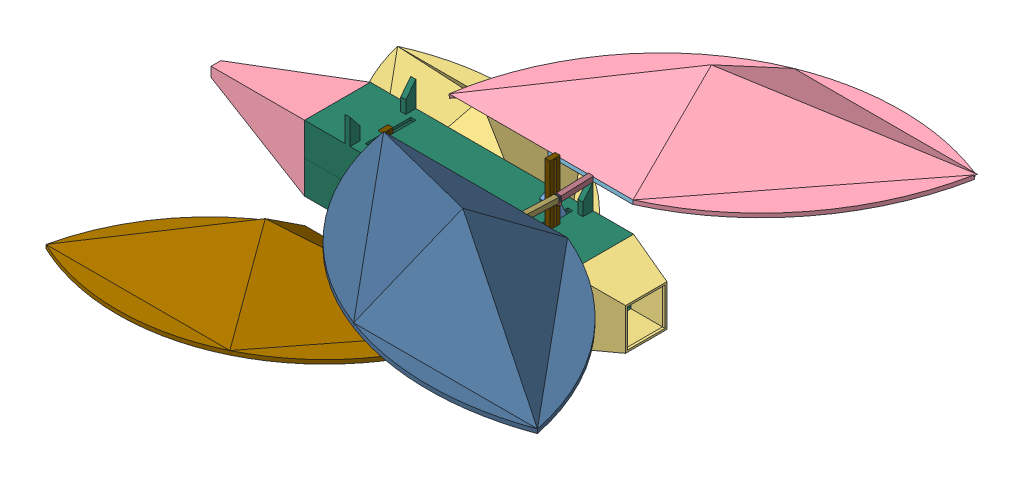
SolidWorks assembly butterfly_CAD_assembly_revised, configuration Default. Lengths in mm.
Overall size (339.79 140.22 297.7).
26 component instances, 22 part files, 59 mates.
Components (placement in the parent):
- part_MECHANICALlargegear_revised-1: part_MECHANICALlargegear_revised [Default] at (-285.4222 85.9127 91.299) x (1 0 0) z (0 -0.999999 0.001095) size (101.6 25.4 6.35)
- part_MECHANICALmotor_revised-1: part_MECHANICALmotor_revised [Default] at (-320.7441 85.9197 97.649) size (24.61 15.88 19.05)
- part_WINGleft-back-1: part_WINGleft-back [Default] at (-467.9022 47.8673 32.872) x (1 0 0) z (0 0.034865 0.999392) size (189.43 39.71 101.22)
- part_WINGleft-front-1: part_WINGleft-front [Default] at (-259.0359 127.2619 18.3121) x (1 0 0) z (0 -0.036788 0.999323) size (214.05 40.94 128.15)
- part_WINGpylon1-1: part_WINGpylon1 [Default] at (-278.8182 118.2238 89.6169) x (1 0 0) z (0 -0.786398 0.61772) size (53.47 17.42 15.33)
- part_WINGpylon2-1: part_WINGpylon2 [Default] at (-389.9432 43.4468 89.9789) x (1 0 0) z (0 -0.740147 0.672445) size (53.47 17.42 15.33)
- part_WINGpylon3-1: part_WINGpylon3 [Default] at (-389.9432 40.9247 125.4869) x (1 0 0) z (0 0.647143 0.762368) size (53.47 15.82 17.01)
- part_WINGpylon4-1: part_WINGpylon4 [Default] at (-278.8182 117.1522 125.9777) x (1 0 0) z (0 0.700073 0.714072) size (53.47 15.82 17.01)
- part_WINGright-back-1: part_WINGright-back [Default] at (-394.7481 47.8673 162.426) x (1 0 0) z (0 -0.034865 0.999392) size (189.43 40.98 101.11)
- part_WINGright-front-1: part_WINGright-front [Default] at (-259.0359 127.2619 176.9858) x (1 0 0) z (0 0.036788 0.999323) size (214.05 40.94 128.46)
- part_WINGsleeve1-1: part_WINGsleeve1 [Default] at (-388.6097 48.0586 76.6029) x (1 0 0) z (0 0.034865 0.999392) size (3.17 3.17 20.32)
- part_WINGsleeve2-1: part_WINGsleeve2 [Default] at (-277.4847 123.0339 98.3843) x (1 0 0) z (0 0.036788 0.999323) size (3.17 3.17 20.32)
- part_WINGsleeve3-1: part_WINGsleeve3 [Default] at (-277.4847 123.7815 76.6074) x (1 0 0) z (0 -0.036788 0.999323) size (3.17 3.17 20.32)
- part_WINGsleeve4-1: part_WINGsleeve4 [Default] at (-388.6097 48.7671 98.3874) x (1 0 0) z (0 -0.034865 0.999392) size (3.17 3.17 20.32)
- part_BODYshell_revised-2: part_BODYshell_revised [Default] at (-250.4972 76.3947 97.649) size (165.1 36.51 41.28)
- part_BODYmotorsupport-1: part_BODYmotorsupport [Default] at (-342.1753 72.4259 97.649) size (3.17 11.11 12.7)
- part_BODYmotorsupport1-1: part_BODYmotorsupport1 [Default] at (-320.7441 72.4259 97.649) size (3.17 11.11 12.7)
- part_MECHANICALrail_revised1-1: part_MECHANICALrail_revised1 [Default] at (-383.8472 67.2666 97.649) size (3.17 78.58 6.35)
- part_MECHANICALrail_revised1-2: part_MECHANICALrail_revised1 [Default] at (-279.0722 104.5728 97.649) size (3.17 78.58 6.35)
- part_MECHANICALpiston_revised-3: part_MECHANICALpiston_revised [Default] at (-282.2472 103.2772 88.9177) x (1 0 0) z (0 0.448979 -0.893542) size (3.17 42.07 6.35)
- part_BODYshell_revised-3: part_BODYshell_revised [Default] at (-250.4972 95.4447 97.649) x (1 0 0) z (0 0 -1) size (165.1 36.51 41.28)
- part_MECHANICALpin_revised-1: part_MECHANICALpin_revised [Default] at (-282.2472 120.6538 97.649) size (9.52 1.59 1.59)
- part_MECHANICALpin_revised-2: part_MECHANICALpin_revised [Default] at (-383.8472 51.1474 97.649) x (-1 0 0) z (0 0 -1) size (9.52 1.59 1.59)
- part_MECHANICALpiston_revised-4: part_MECHANICALpiston_revised [Default] at (-380.6722 68.524 88.9177) x (1 0 0) z (0 0.448979 0.893542) size (3.17 42.07 6.35)
- part_BODYnosecone_revised-1: part_BODYnosecone_revised [Default] at (-250.4972 87.5072 96.0615) size (28.57 41.28 41.28)
- part_BODYabdomencone_revised-1: part_BODYabdomencone_revised [Default] at (-415.5972 85.9197 97.649) size (76.2 41.27 41.27)
Mates (geometry in assembly coordinates):
- Concentric1: concentric aligned: cylinder of part_MECHANICALlargegear_revised-1 through (-377.4972 85.9197 97.649) axis (1 0 0) radius 0.7937; cylinder of part_MECHANICALmotor_revised-1 through (-345.3503 85.9197 97.649) axis (1 0 0) radius 0.7937
- Coincident1: coincident aligned: line of part_MECHANICALmotor_revised-1 through (-345.3503 77.9822 103.999) axis (1 0 0); line of part_BODYmotorsupport-1 through (-345.3503 77.9822 103.999) axis (1 0 0)
- Coincident2: coincident anti-aligned: line of part_MECHANICALmotor_revised-1 through (-345.3503 77.9822 103.999) axis (0 0 -1); line of part_BODYmotorsupport-1 through (-345.3503 77.9822 91.299) axis (0 0 1)
- Coincident4: coincident aligned: line of part_MECHANICALmotor_revised-1 through (-345.3503 77.9822 103.999) axis (1 0 0); line of part_BODYmotorsupport1-1 through (-323.9191 77.9822 103.999) axis (1 0 0)
- Coincident5: coincident anti-aligned: line of part_MECHANICALmotor_revised-1 through (-320.7441 77.9822 103.999) axis (0 0 -1); line of part_BODYmotorsupport1-1 through (-320.7441 77.9822 91.299) axis (0 0 1)
- Coincident6: coincident aligned: line of part_BODYshell_revised-2 through (-320.7441 66.8697 103.999) axis (0 0 -1); line of part_BODYmotorsupport1-1 through (-320.7441 66.8697 103.999) axis (0 0 -1)
- Coincident8: coincident aligned: line of part_BODYshell_revised-2 through (-345.3503 66.8697 103.999) axis (1 0 0); line of part_BODYmotorsupport-1 through (-345.3503 66.8697 103.999) axis (1 0 0)
- Symmetric1: symmetric anti-aligned: line of part_MECHANICALlargegear_revised-1 through (-288.5972 89.1016 103.9955) axis (0 -0.999999 0.001095); line of part_MECHANICALlargegear_revised-1 through (-377.4972 82.7516 104.0024) axis (0 0.999999 -0.001095); plane of assembly
- Coincident11: coincident anti-aligned: line of part_BODYshell_revised-2 through (-279.0722 65.2822 94.474) axis (0 0 1); line of part_MECHANICALrail_revised1-2 through (-279.0722 65.2822 100.824) axis (0 0 -1)
- Coincident12: coincident anti-aligned: line of part_BODYshell_revised-2 through (-279.0722 65.2822 100.824) axis (-1 0 0); line of part_MECHANICALrail_revised1-2 through (-282.2472 65.2822 100.824) axis (1 0 0)
- Coincident16: coincident aligned: circle of part_MECHANICALlargegear_revised-1; circle of part_MECHANICALpiston_revised-3
- Coincident17: coincident aligned: line of part_BODYshell_revised-2 through (-415.5972 85.9197 118.2865) axis (1 0 0); line of part_BODYshell_revised-3 through (-415.5972 85.9197 118.2865) axis (1 0 0)
- Coincident18: coincident anti-aligned: line of part_BODYshell_revised-2 through (-250.4972 85.9197 116.699) axis (0 0 1); line of part_BODYshell_revised-3 through (-250.4972 85.9197 118.2865) axis (0 0 -1)
- Coincident19: coincident aligned: circle of part_MECHANICALpiston_revised-3; circle of part_MECHANICALpin_revised-1
- Coincident20: coincident aligned: line of part_MECHANICALrail_revised1-2 through (-282.2472 66.0759 96.8552) axis (0 1 0); line of part_MECHANICALpin_revised-1 through (-282.2472 120.6538 96.8552) axis (0 1 0)
- Coincident21: coincident anti-aligned: circle of part_MECHANICALpin_revised-2; circle of part_MECHANICALpiston_revised-4
- Coincident22: coincident anti-aligned: circle of part_MECHANICALlargegear_revised-1; circle of part_MECHANICALpiston_revised-4
- Coincident25: coincident anti-aligned: line of part_MECHANICALrail_revised1-1 through (-383.8472 105.7634 98.4427) axis (0 -1 0); line of part_MECHANICALpin_revised-2 through (-383.8472 50.3536 98.4427) axis (0 1 0)
- Coincident26: coincident anti-aligned: line of part_WINGsleeve2-1 through (-279.0722 121.4475 98.4427) axis (1 0 0); line of part_MECHANICALpin_revised-1 through (-275.8972 121.4475 98.4427) axis (-1 0 0)
- Coincident27: coincident: point of part_WINGsleeve2-1; point of part_MECHANICALpin_revised-1
- Coincident28: coincident anti-aligned: line of part_WINGsleeve3-1 through (-279.0722 121.4475 96.8552) axis (1 0 0); line of part_MECHANICALpin_revised-1 through (-275.8972 121.4475 96.8552) axis (-1 0 0)
- Coincident29: coincident: point of part_WINGsleeve3-1; point of part_MECHANICALpin_revised-1
- Coincident30: coincident anti-aligned: line of part_WINGsleeve1-1 through (-387.0222 50.3536 96.8552) axis (-1 0 0); line of part_MECHANICALpin_revised-2 through (-390.1972 50.3536 96.8552) axis (1 0 0)
- Coincident34: coincident: point of part_WINGsleeve1-1; point of part_MECHANICALpin_revised-2
- Coincident35: coincident anti-aligned: line of part_WINGsleeve4-1 through (-387.0222 50.3536 98.4427) axis (-1 0 0); line of part_MECHANICALpin_revised-2 through (-390.1972 50.3536 98.4427) axis (1 0 0)
- Coincident36: coincident: point of part_WINGsleeve4-1; point of part_MECHANICALpin_revised-2
- Coincident37: coincident aligned: line of part_WINGpylon4-1 through (-278.8182 122.4322 118.2865) axis (0 -0.036788 -0.999323); line of part_WINGsleeve2-1 through (-278.8182 122.4489 118.7396) axis (0 -0.036788 -0.999323)
- Coincident38: coincident aligned: line of part_WINGpylon4-1 through (-276.1512 122.4322 118.2865) axis (0 -0.036788 -0.999323); line of part_WINGsleeve2-1 through (-276.1512 122.4489 118.7396) axis (0 -0.036788 -0.999323)
- Coincident40: coincident anti-aligned: line of part_WINGpylon1-1 through (-276.1512 122.4322 77.0115) axis (0 -0.036788 0.999323); line of part_WINGsleeve3-1 through (-276.1512 121.7013 96.8646) axis (0 0.036788 -0.999323)
- Coincident41: coincident aligned: line of part_WINGpylon1-1 through (-278.8182 124.3499 97.4158) axis (0 0.036788 -0.999323); line of part_WINGsleeve3-1 through (-278.8182 124.3665 96.9627) axis (0 0.036788 -0.999323)
- Coincident42: coincident aligned: line of part_WINGpylon3-1 through (-389.9432 46.7418 118.1935) axis (0 0.034865 -0.999392); line of part_WINGsleeve4-1 through (-389.9432 46.7259 118.6485) axis (0 0.034865 -0.999392)
- Coincident43: coincident anti-aligned: line of part_WINGpylon3-1 through (-387.2762 50.1156 97.9788) axis (0 -0.034865 0.999392); line of part_WINGsleeve4-1 through (-387.2762 49.3913 118.7415) axis (0 0.034865 -0.999392)
- Coincident47: coincident aligned: line of part_WINGpylon4-1 through (-276.1512 122.4322 118.2865) axis (-1 0 0); line of part_BODYshell_revised-3 through (-275.8972 122.4322 118.2865) axis (-1 0 0)
- Coincident48: coincident anti-aligned: line of part_WINGpylon1-1 through (-278.8182 122.4322 77.0115) axis (1 0 0); line of part_BODYshell_revised-3 through (-275.8972 122.4322 77.0115) axis (-1 0 0)
- Coincident49: coincident anti-aligned: line of part_WINGpylon3-1 through (-389.9432 49.4072 118.2865) axis (1 0 0); line of part_BODYshell_revised-2 through (-387.0222 49.4072 118.2865) axis (-1 0 0)
- Coincident52: coincident anti-aligned: line of part_WINGpylon2-1 through (-389.9432 46.7418 77.1044) axis (0 0.034865 0.999392); line of part_WINGsleeve1-1 through (-389.9432 47.4344 96.9571) axis (0 -0.034865 -0.999392)
- Coincident53: coincident aligned: line of part_WINGpylon2-1 through (-387.2762 50.1156 97.3191) axis (0 -0.034865 -0.999392); line of part_WINGsleeve1-1 through (-387.2762 50.0998 96.8641) axis (0 -0.034865 -0.999392)
- Coincident54: coincident anti-aligned: line of part_WINGpylon2-1 through (-389.9432 49.4072 77.0115) axis (1 0 0); line of part_BODYshell_revised-2 through (-387.0222 49.4072 77.0115) axis (-1 0 0)
- Coincident63: coincident anti-aligned: line of part_WINGpylon4-1 through (-276.1512 125.0974 118.1884) axis (1 0 0); line of part_WINGright-front-1 through (-250.7512 125.0974 118.1884) axis (-1 0 0)
- Coincident64: coincident: point of part_WINGpylon4-1; point of part_WINGright-front-1
- Coincident65: coincident: line of part_WINGpylon4-1 through (-304.2182 125.1067 118.4422) axis (1 0 0); plane of part_WINGright-front-1 through (-259.0359 127.2619 176.9858) normal (0 -0.999323 0.036788)
- Coincident66: coincident anti-aligned: line of part_WINGleft-front-1 through (-250.7512 125.0974 77.1096) axis (-1 0 0); line of part_WINGpylon1-1 through (-276.1512 125.0974 77.1096) axis (1 0 0)
- Coincident67: coincident: point of part_WINGleft-front-1; point of part_WINGpylon1-1
- Coincident68: coincident: plane of part_WINGleft-front-1 through (-259.0359 127.2619 18.3121) normal (0 -0.999323 -0.036788); line of part_WINGpylon1-1 through (-304.2182 125.1067 76.8558) axis (1 0 0)
- Coincident69: coincident anti-aligned: line of part_WINGpylon3-1 through (-387.2762 49.4072 118.2865) axis (1 0 0); line of part_WINGright-back-1 through (-300.0331 49.4072 118.2865) axis (-1 0 0)
- Coincident70: coincident: point of part_WINGpylon3-1; point of part_WINGright-back-1
- Coincident72: coincident: line of part_WINGpylon3-1 through (-415.3432 49.3983 118.5403) axis (1 0 0); plane of part_WINGright-back-1 through (-394.7481 47.8673 162.426) normal (0 -0.999392 -0.034865)
- Coincident73: coincident aligned: line of part_WINGleft-back-1 through (-412.6762 49.4072 77.0115) axis (1 0 0); line of part_WINGpylon2-1 through (-387.2762 49.4072 77.0115) axis (1 0 0)
- Coincident74: coincident: point of part_WINGleft-back-1; point of part_WINGpylon2-1
- Coincident75: coincident: plane of part_WINGleft-back-1 through (-467.9022 47.8673 32.872) normal (0 -0.999392 0.034865); line of part_WINGpylon2-1 through (-412.6762 49.3983 76.7576) axis (1 0 0)
- Lock1: lock: unknown of part_BODYshell_revised-2
- Coincident78: coincident aligned: line of part_BODYshell_revised-3 through (-250.4972 106.5572 118.2865) axis (0 -1 0); line of part_BODYnosecone_revised-1 through (-250.4972 106.5572 118.2865) axis (0 -1 0)
- Coincident79: coincident: point of part_BODYshell_revised-2; point of part_BODYnosecone_revised-1
- Coincident80: coincident aligned: line of part_BODYshell_revised-2 through (-250.4972 65.2822 77.0115) axis (0 1 0); line of part_BODYnosecone_revised-1 through (-250.4972 65.2822 77.0115) axis (0 1 0)
- Coincident81: coincident aligned: line of part_BODYshell_revised-3 through (-415.5972 106.5572 118.2865) axis (0 -1 0); line of part_BODYabdomencone_revised-1 through (-415.5972 106.5572 118.2865) axis (0 -1 0)
- Coincident82: coincident: point of part_BODYshell_revised-2; point of part_BODYabdomencone_revised-1
- Coincident83: coincident aligned: line of part_BODYshell_revised-2 through (-415.5972 65.2822 77.0115) axis (0 1 0); line of part_BODYabdomencone_revised-1 through (-415.5972 65.2822 77.0115) axis (0 1 0)
- Coincident87: coincident aligned: line of part_MECHANICALrail_revised1-1 through (-387.0222 106.5572 94.474) axis (0 0 1); line of part_BODYshell_revised-3 through (-387.0222 106.5572 94.474) axis (0 0 1)
- Coincident88: coincident anti-aligned: line of part_MECHANICALrail_revised1-1 through (-387.0222 106.5572 94.474) axis (1 0 0); line of part_BODYshell_revised-3 through (-383.8472 106.5572 94.474) axis (-1 0 0)
